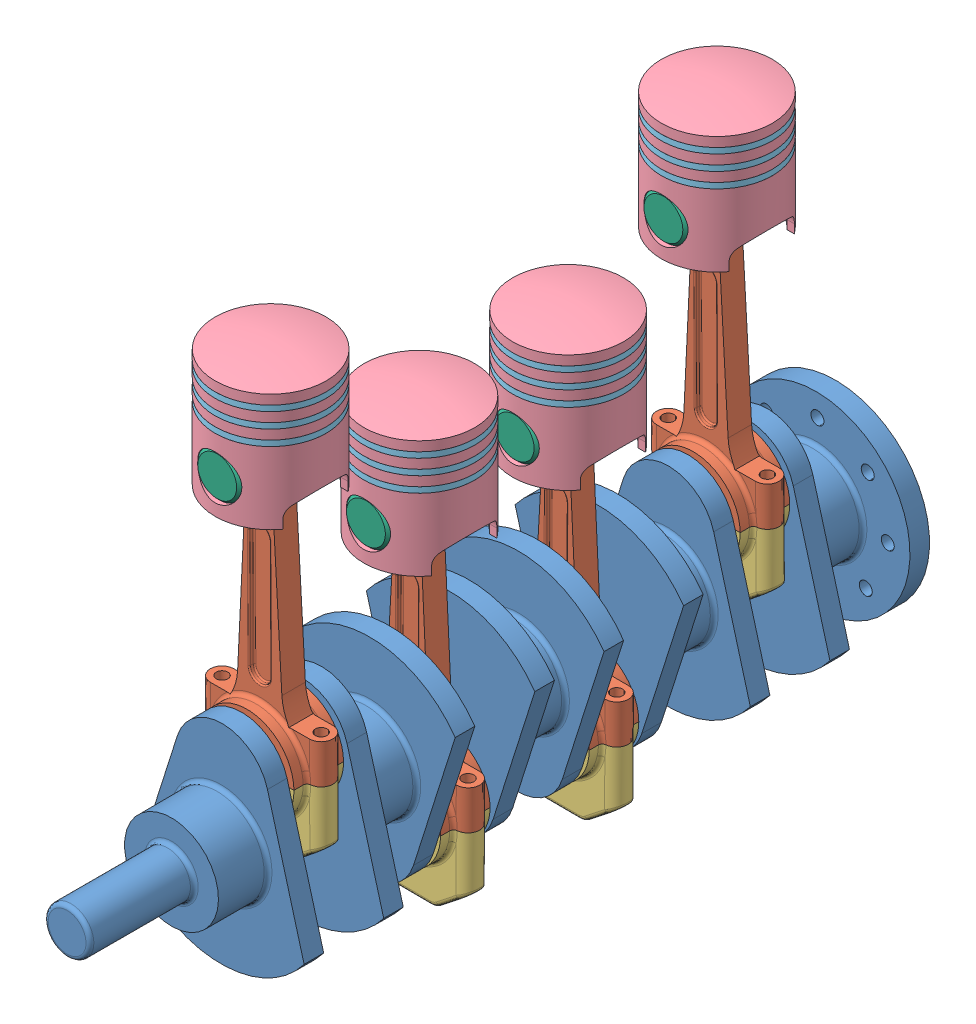
SolidWorks assembly Engine 2003082, configuration Default. Lengths in mm.
Overall size (147.06 418.41 589).
29 component instances, 6 part files, 66 mates.
Components (placement in the parent):
- Crankshaft-1: Crankshaft [Default] at (0 0 456) x (-0.999814 0.019293 0) z (0 0 1) size (144 160 589)
- Connecting rod-1: Connecting rod [Default] at (0 245.19 433) x (0.999991 0.004219 0) z (0 0 1) size (94 223.7 38)
- Connecting rod cap-1: Connecting rod cap [Default] at (0.8489 43.9918 433) x (-0.999991 -0.004219 0) z (0 0 1) size (94 60 38)
- Piston-1: Piston [Default] at (0 219.2199 433) size (85 95 85)
- Piston ring-1: Piston ring [Default] at (0 297.6199 433) size (85 4.3 85)
- Piston Pin-1: Piston Pin [Default] at (0 245.19 433) size (33.8 33.8 82)
- Piston ring-2: Piston ring [Default] at (0 286.0199 433) x (0.546944 0 -0.837169) z (0.837169 0 0.546944) size (85 4.3 85)
- Piston ring-4: Piston ring [Default] at (0 274.4199 433) x (0.546944 0 -0.837169) z (0.837169 0 0.546944) size (85 4.3 85)
- Piston-2: Piston [Default] at (0 131.2362 319) size (85 95 85)
- Piston ring-6: Piston ring [Default] at (0 209.6362 319) x (0.941458 0 -0.337131) z (0.337131 0 0.941458) size (85 4.3 85)
- Piston ring-7: Piston ring [Default] at (0 198.0362 319) x (0.23269 0 -0.972551) z (0.972551 0 0.23269) size (85 4.3 85)
- Piston ring-8: Piston ring [Default] at (0 186.4362 319) x (0.23269 0 -0.972551) z (0.972551 0 0.23269) size (85 4.3 85)
- Piston Pin-2: Piston Pin [Default] at (0 157.2064 319) x (0.216826 -0.97621 0) z (0 0 1) size (33.8 33.8 82)
- Connecting rod-2: Connecting rod [Default] at (0 157.2064 319) x (0.999991 -0.004219 0) z (0 0 1) size (94 223.7 38)
- Connecting rod cap-2: Connecting rod cap [Default] at (-0.8489 -43.9918 319) x (-0.999991 0.004219 0) z (0 0 1) size (94 60 38)
- Piston-4: Piston [Default] at (0 131.2362 205) x (-1 0 0) z (0 0 -1) size (85 95 85)
- Piston ring-12: Piston ring [Default] at (0 209.6362 205) x (0.790546 0 -0.612403) z (0.612403 0 0.790546) size (85 4.3 85)
- Piston ring-13: Piston ring [Default] at (0 198.0362 205) x (-0.0803 0 -0.996771) z (0.996771 0 -0.0803) size (85 4.3 85)
- Piston ring-14: Piston ring [Default] at (0 186.4362 205) x (-0.0803 0 -0.996771) z (0.996771 0 -0.0803) size (85 4.3 85)
- Piston Pin-4: Piston Pin [Default] at (0 157.2064 205) x (-0.34202 0.939693 0) z (0 0 -1) size (33.8 33.8 82)
- Connecting rod-4: Connecting rod [Default] at (0 157.2064 205) x (-0.999991 0.004219 0) z (0 0 -1) size (94 223.7 38)
- Connecting rod cap-4: Connecting rod cap [Default] at (-0.8489 -43.9918 205) x (0.999991 -0.004219 0) z (0 0 -1) size (94 60 38)
- Piston-6: Piston [Default] at (0 219.2199 91) x (-1 0 0) z (0 0 -1) size (85 95 85)
- Piston ring-18: Piston ring [Default] at (0 297.6199 91) x (0.6 0 -0.8) z (0.8 0 0.6) size (85 4.3 85)
- Piston ring-19: Piston ring [Default] at (0 286.0199 91) x (-0.341569 0 -0.939857) z (0.939857 0 -0.341569) size (85 4.3 85)
- Piston ring-20: Piston ring [Default] at (0 274.4199 91) x (-0.341569 0 -0.939857) z (0.939857 0 -0.341569) size (85 4.3 85)
- Piston Pin-6: Piston Pin [Default] at (0 245.19 91) x (-0.5 0.866025 0) z (0 0 -1) size (33.8 33.8 82)
- Connecting rod-6: Connecting rod [Default] at (0 245.19 91) x (-0.999991 -0.004219 0) z (0 0 -1) size (94 223.7 38)
- Connecting rod cap-6: Connecting rod cap [Default] at (0.8489 43.9918 91) x (0.999991 0.004219 0) z (0 0 -1) size (94 60 38)
Mates (geometry in assembly coordinates):
- Concentric1: concentric anti-aligned: cylinder of Crankshaft-1 through (0 0 589) axis (0 0 -1) radius 17.5
- Coincident1: coincident: plane of Crankshaft-1 through (0 0 589) normal (0 0 1)
- Coincident2: coincident aligned: plane of Piston-1 through (0 219.2199 433) normal (0 0 1); plane of Piston Pin-1 through (0 245.19 433) normal (0 0 1)
- Concentric2: concentric anti-aligned: cylinder of Piston-1 through (0 245.19 390.5) axis (0 0 1) radius 16.9; cylinder of Piston Pin-1 through (0 245.19 474) axis (0 0 -1) radius 16.9
- Concentric3: concentric aligned: cylinder of Piston-1 through (0 309.2199 433) axis (0 -1 0) radius 42.5; cylinder of Piston ring-1 through (0 301.9199 433) axis (0 -1 0) radius 42.5
- Coincident3: coincident anti-aligned: plane of Piston-1 through (0 297.6199 433) normal (0 1 0); plane of Piston ring-1 through (0 297.6199 433) normal (0 -1 0)
- Concentric4: concentric anti-aligned: cylinder of Piston-1 through (0 286.0199 433) axis (0 1 0) radius 39.5; cylinder of Piston ring-2 through (0 290.3199 433) axis (0 -1 0) radius 42.5
- Coincident4: coincident anti-aligned: plane of Piston-1 through (0 286.0199 433) normal (0 1 0); plane of Piston ring-2 through (0 286.0199 433) normal (0 -1 0)
- Concentric5: concentric anti-aligned: cylinder of Piston-1 through (0 274.4199 433) axis (0 1 0) radius 39.5; cylinder of Piston ring-4 through (0 278.7199 433) axis (0 -1 0) radius 42.5
- Coincident5: coincident anti-aligned: plane of Piston-1 through (0 274.4199 433) normal (0 1 0); plane of Piston ring-4 through (0 274.4199 433) normal (0 -1 0)
- Coincident6: coincident aligned: plane of Connecting rod-1 through (0 245.19 433) normal (0 0 1); plane of Piston-1 through (0 219.2199 433) normal (0 0 1)
- Concentric6: concentric aligned: cylinder of Connecting rod-1 through (0 245.19 452) axis (0 0 -1) radius 16.9; cylinder of Piston Pin-1 through (0 245.19 474) axis (0 0 -1) radius 16.9
- Concentric7: concentric aligned: cylinder of Connecting rod-1 through (38.8486 44.1521 433) axis (-0.004219 0.999991 0) radius 4.5; cylinder of Connecting rod cap-1 through (39.1017 -15.8473 433) axis (-0.004219 0.999991 0) radius 4.5
- Concentric8: concentric aligned: cylinder of Connecting rod-1 through (-37.1508 43.8315 433) axis (-0.004219 0.999991 0) radius 4.5; cylinder of Connecting rod cap-1 through (-36.8976 -16.168 433) axis (-0.004219 0.999991 0) radius 4.5
- Coincident7: coincident anti-aligned: plane of Connecting rod-1 through (0.8489 43.9918 452) normal (0.004219 -0.999991 0); plane of Connecting rod cap-1 through (36.8486 44.1437 452) normal (-0.004219 0.999991 0)
- Width1: width anti-aligned: plane of Crankshaft-1 through (0 0 410) normal (0 0 1); plane of Crankshaft-1 through (0 0 456) normal (0 0 -1); plane of Connecting rod-1 through (0 245.19 424) normal (0 0 -1); plane of Connecting rod-1 through (0 245.19 442) normal (0 0 1)
- Concentric9: concentric anti-aligned: cylinder of Crankshaft-1 through (0.8489 43.9918 410) axis (0 0 1) radius 27; cylinder of Connecting rod-1 through (0.8489 43.9918 452) axis (0 0 -1) radius 27
- Concentric10: concentric anti-aligned: cylinder of Piston-1 through (0 309.2199 433) axis (0 -1 0) radius 42.5
- Coincident9: coincident aligned: plane of Piston-2 through (0 131.2362 319) normal (0 0 1); plane of Piston Pin-2 through (0 157.2064 319) normal (0 0 1)
- Concentric11: concentric anti-aligned: cylinder of Piston-2 through (0 157.2064 276.5) axis (0 0 1) radius 16.9; cylinder of Piston Pin-2 through (0 157.2064 360) axis (0 0 -1) radius 16.9
- Concentric12: concentric aligned: cylinder of Piston-2 through (0 221.2362 319) axis (0 -1 0) radius 42.5; cylinder of Piston ring-6 through (0 213.9362 319) axis (0 -1 0) radius 42.5
- Coincident10: coincident anti-aligned: plane of Piston-2 through (0 209.6362 319) normal (0 1 0); plane of Piston ring-6 through (0 209.6362 319) normal (0 -1 0)
- Concentric13: concentric anti-aligned: cylinder of Piston-2 through (0 198.0362 319) axis (0 1 0) radius 39.5; cylinder of Piston ring-7 through (0 202.3362 319) axis (0 -1 0) radius 42.5
- Coincident11: coincident anti-aligned: plane of Piston-2 through (0 198.0362 319) normal (0 1 0); plane of Piston ring-7 through (0 198.0362 319) normal (0 -1 0)
- Concentric14: concentric anti-aligned: cylinder of Piston-2 through (0 186.4362 319) axis (0 1 0) radius 39.5; cylinder of Piston ring-8 through (0 190.7362 319) axis (0 -1 0) radius 42.5
- Coincident12: coincident anti-aligned: plane of Piston-2 through (0 186.4362 319) normal (0 1 0); plane of Piston ring-8 through (0 186.4362 319) normal (0 -1 0)
- Coincident13: coincident aligned: plane of Piston-2 through (0 131.2362 319) normal (0 0 1); plane of Connecting rod-2 through (0 157.2064 319) normal (0 0 1)
- Concentric15: concentric aligned: cylinder of Piston Pin-2 through (0 157.2064 360) axis (0 0 -1) radius 16.9; cylinder of Connecting rod-2 through (0 157.2064 338) axis (0 0 -1) radius 16.9
- Concentric16: concentric aligned: cylinder of Connecting rod-2 through (37.1508 -44.1521 319) axis (0.004219 0.999991 0) radius 4.5; cylinder of Connecting rod cap-2 through (36.8976 -104.1516 319) axis (0.004219 0.999991 0) radius 4.5
- Concentric17: concentric aligned: cylinder of Connecting rod-2 through (-38.8486 -43.8315 319) axis (0.004219 0.999991 0) radius 4.5; cylinder of Connecting rod cap-2 through (-39.1017 -103.8309 319) axis (0.004219 0.999991 0) radius 4.5
- Coincident14: coincident anti-aligned: plane of Connecting rod-2 through (-0.8489 -43.9918 338) normal (-0.004219 -0.999991 0); plane of Connecting rod cap-2 through (35.1508 -44.1437 338) normal (0.004219 0.999991 0)
- Width2: width anti-aligned: plane of Crankshaft-1 through (0 0 342) normal (0 0 -1); plane of Crankshaft-1 through (0 0 296) normal (0 0 1); plane of Connecting rod-2 through (0 157.2064 310) normal (0 0 -1); plane of Connecting rod-2 through (0 157.2064 328) normal (0 0 1)
- Concentric18: concentric anti-aligned: cylinder of Crankshaft-1 through (-0.8489 -43.9918 296) axis (0 0 1) radius 27; cylinder of Connecting rod-2 through (-0.8489 -43.9918 338) axis (0 0 -1) radius 27
- Concentric19: concentric anti-aligned: cylinder of Piston-2 through (0 221.2362 319) axis (0 -1 0) radius 42.5
- Coincident21: coincident aligned: plane of Piston-4 through (0 131.2362 205) normal (0 0 -1); plane of Piston Pin-4 through (0 157.2064 205) normal (0 0 -1)
- Concentric27: concentric anti-aligned: cylinder of Piston-4 through (0 157.2064 247.5) axis (0 0 -1) radius 16.9; cylinder of Piston Pin-4 through (0 157.2064 164) axis (0 0 1) radius 16.9
- Concentric28: concentric aligned: cylinder of Piston-4 through (0 221.2362 205) axis (0 -1 0) radius 42.5; cylinder of Piston ring-12 through (0 213.9362 205) axis (0 -1 0) radius 42.5
- Coincident22: coincident anti-aligned: plane of Piston-4 through (0 209.6362 205) normal (0 1 0); plane of Piston ring-12 through (0 209.6362 205) normal (0 -1 0)
- Concentric29: concentric anti-aligned: cylinder of Piston-4 through (0 198.0362 205) axis (0 1 0) radius 39.5; cylinder of Piston ring-13 through (0 202.3362 205) axis (0 -1 0) radius 42.5
- Coincident23: coincident anti-aligned: plane of Piston-4 through (0 198.0362 205) normal (0 1 0); plane of Piston ring-13 through (0 198.0362 205) normal (0 -1 0)
- Concentric30: concentric anti-aligned: cylinder of Piston-4 through (0 186.4362 205) axis (0 1 0) radius 39.5; cylinder of Piston ring-14 through (0 190.7362 205) axis (0 -1 0) radius 42.5
- Coincident24: coincident anti-aligned: plane of Piston-4 through (0 186.4362 205) normal (0 1 0); plane of Piston ring-14 through (0 186.4362 205) normal (0 -1 0)
- Coincident25: coincident aligned: plane of Piston-4 through (0 131.2362 205) normal (0 0 -1); plane of Connecting rod-4 through (0 157.2064 205) normal (0 0 -1)
- Concentric31: concentric aligned: cylinder of Piston Pin-4 through (0 157.2064 164) axis (0 0 1) radius 16.9; cylinder of Connecting rod-4 through (0 157.2064 186) axis (0 0 1) radius 16.9
- Concentric32: concentric aligned: cylinder of Connecting rod-4 through (-38.8486 -43.8315 205) axis (0.004219 0.999991 0) radius 4.5; cylinder of Connecting rod cap-4 through (-39.1017 -103.8309 205) axis (0.004219 0.999991 0) radius 4.5
- Concentric33: concentric aligned: cylinder of Connecting rod-4 through (37.1508 -44.1521 205) axis (0.004219 0.999991 0) radius 4.5; cylinder of Connecting rod cap-4 through (36.8976 -104.1516 205) axis (0.004219 0.999991 0) radius 4.5
- Coincident26: coincident anti-aligned: plane of Connecting rod-4 through (-0.8489 -43.9918 186) normal (-0.004219 -0.999991 0); plane of Connecting rod cap-4 through (-36.8486 -43.8399 186) normal (0.004219 0.999991 0)
- Width3: width anti-aligned: plane of Crankshaft-1 through (0 0 228) normal (0 0 -1); plane of Crankshaft-1 through (0 0 182) normal (0 0 1); plane of Connecting rod-4 through (0 157.2064 214) normal (0 0 1); plane of Connecting rod-4 through (0 157.2064 196) normal (0 0 -1)
- Concentric34: concentric anti-aligned: cylinder of Crankshaft-1 through (-0.8489 -43.9918 228) axis (0 0 -1) radius 27; cylinder of Connecting rod-4 through (-0.8489 -43.9918 186) axis (0 0 1) radius 27
- Concentric35: concentric anti-aligned: cylinder of Piston-4 through (0 221.2362 205) axis (0 -1 0) radius 42.5
- Coincident33: coincident aligned: plane of Piston-6 through (0 219.2199 91) normal (0 0 -1); plane of Piston Pin-6 through (0 245.19 91) normal (0 0 -1)
- Concentric43: concentric anti-aligned: cylinder of Piston-6 through (0 245.19 133.5) axis (0 0 -1) radius 16.9; cylinder of Piston Pin-6 through (0 245.19 50) axis (0 0 1) radius 16.9
- Concentric44: concentric aligned: cylinder of Piston-6 through (0 309.2199 91) axis (0 -1 0) radius 42.5; cylinder of Piston ring-18 through (0 301.9199 91) axis (0 -1 0) radius 42.5
- Coincident34: coincident anti-aligned: plane of Piston-6 through (0 297.6199 91) normal (0 1 0); plane of Piston ring-18 through (0 297.6199 91) normal (0 -1 0)
- Concentric45: concentric anti-aligned: cylinder of Piston-6 through (0 286.0199 91) axis (0 1 0) radius 39.5; cylinder of Piston ring-19 through (0 290.3199 91) axis (0 -1 0) radius 42.5
- Coincident35: coincident anti-aligned: plane of Piston-6 through (0 286.0199 91) normal (0 1 0); plane of Piston ring-19 through (0 286.0199 91) normal (0 -1 0)
- Concentric46: concentric anti-aligned: cylinder of Piston-6 through (0 274.4199 91) axis (0 1 0) radius 39.5; cylinder of Piston ring-20 through (0 278.7199 91) axis (0 -1 0) radius 42.5
- Coincident36: coincident anti-aligned: plane of Piston-6 through (0 274.4199 91) normal (0 1 0); plane of Piston ring-20 through (0 274.4199 91) normal (0 -1 0)
- Coincident37: coincident aligned: plane of Piston-6 through (0 219.2199 91) normal (0 0 -1); plane of Connecting rod-6 through (0 245.19 91) normal (0 0 -1)
- Concentric47: concentric aligned: cylinder of Piston Pin-6 through (0 245.19 50) axis (0 0 1) radius 16.9; cylinder of Connecting rod-6 through (0 245.19 72) axis (0 0 1) radius 16.9
- Concentric48: concentric aligned: cylinder of Connecting rod-6 through (-37.1508 43.8315 91) axis (-0.004219 0.999991 0) radius 4.5; cylinder of Connecting rod cap-6 through (-36.8976 -16.168 91) axis (-0.004219 0.999991 0) radius 4.5
- Concentric49: concentric aligned: cylinder of Connecting rod-6 through (38.8486 44.1521 91) axis (-0.004219 0.999991 0) radius 4.5; cylinder of Connecting rod cap-6 through (39.1017 -15.8473 91) axis (-0.004219 0.999991 0) radius 4.5
- Coincident38: coincident anti-aligned: plane of Connecting rod-6 through (0.8489 43.9918 72) normal (0.004219 -0.999991 0); plane of Connecting rod cap-6 through (-35.1508 43.8399 72) normal (-0.004219 0.999991 0)
- Width4: width anti-aligned: plane of Crankshaft-1 through (0 0 114) normal (0 0 -1); plane of Crankshaft-1 through (0 0 68) normal (0 0 1); plane of Connecting rod-6 through (0 245.19 100) normal (0 0 1); plane of Connecting rod-6 through (0 245.19 82) normal (0 0 -1)
- Concentric50: concentric anti-aligned: cylinder of Crankshaft-1 through (0.8489 43.9918 114) axis (0 0 -1) radius 27; cylinder of Connecting rod-6 through (0.8489 43.9918 72) axis (0 0 1) radius 27
- Concentric51: concentric anti-aligned: cylinder of Piston-6 through (0 309.2199 91) axis (0 -1 0) radius 42.5
